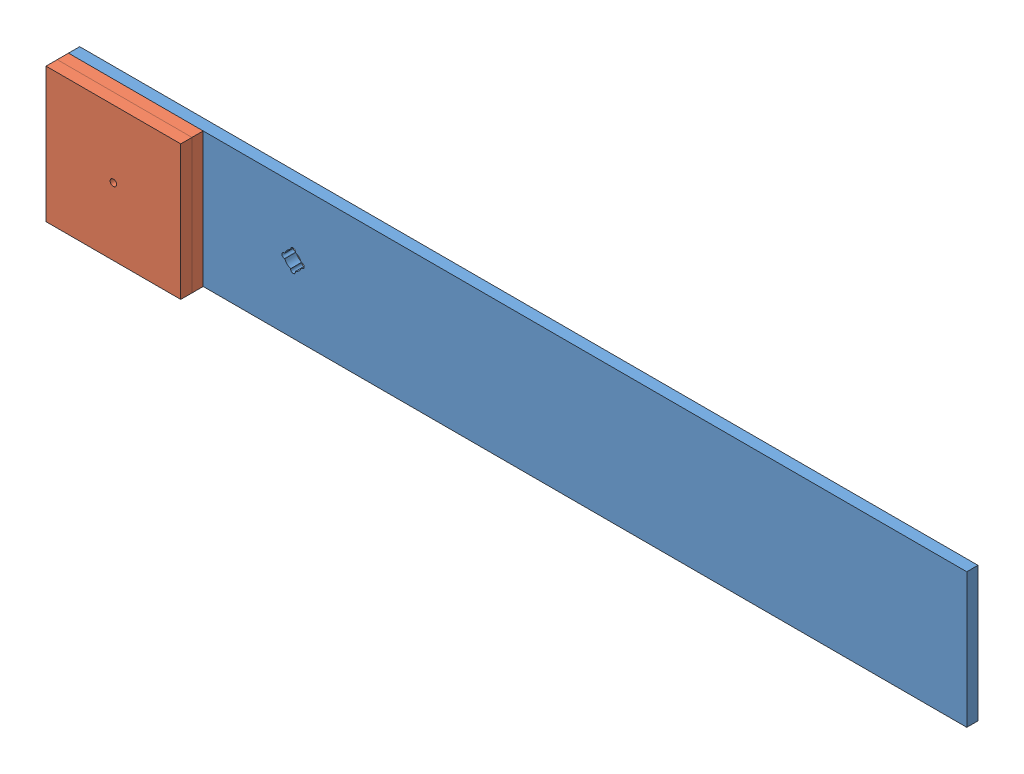
SolidWorks assembly asus_mount_assembly, configuration Default. Lengths in mm.
Overall size (508 76.2 19.05).
3 component instances, 2 part files, 2 mates.
Components (placement in the parent):
- asus_mount-1: asus_mount [Default] at (-233.0747 -48.0936 -7.4275) size (508 76.2 6.35)
- asus_mount_weights-1: asus_mount_weights [Default] at (-233.0747 -48.0936 -1.0775) size (76.2 76.2 6.35)
- asus_mount_weights-2: asus_mount_weights [Default] at (-233.0747 -48.0936 5.2725) size (76.2 76.2 6.35)
Mates (geometry in assembly coordinates):
- Coincident1: coincident aligned: circle of asus_mount-1; circle of asus_mount_weights-1
- Coincident2: coincident aligned: circle of asus_mount_weights-1; circle of asus_mount_weights-2
